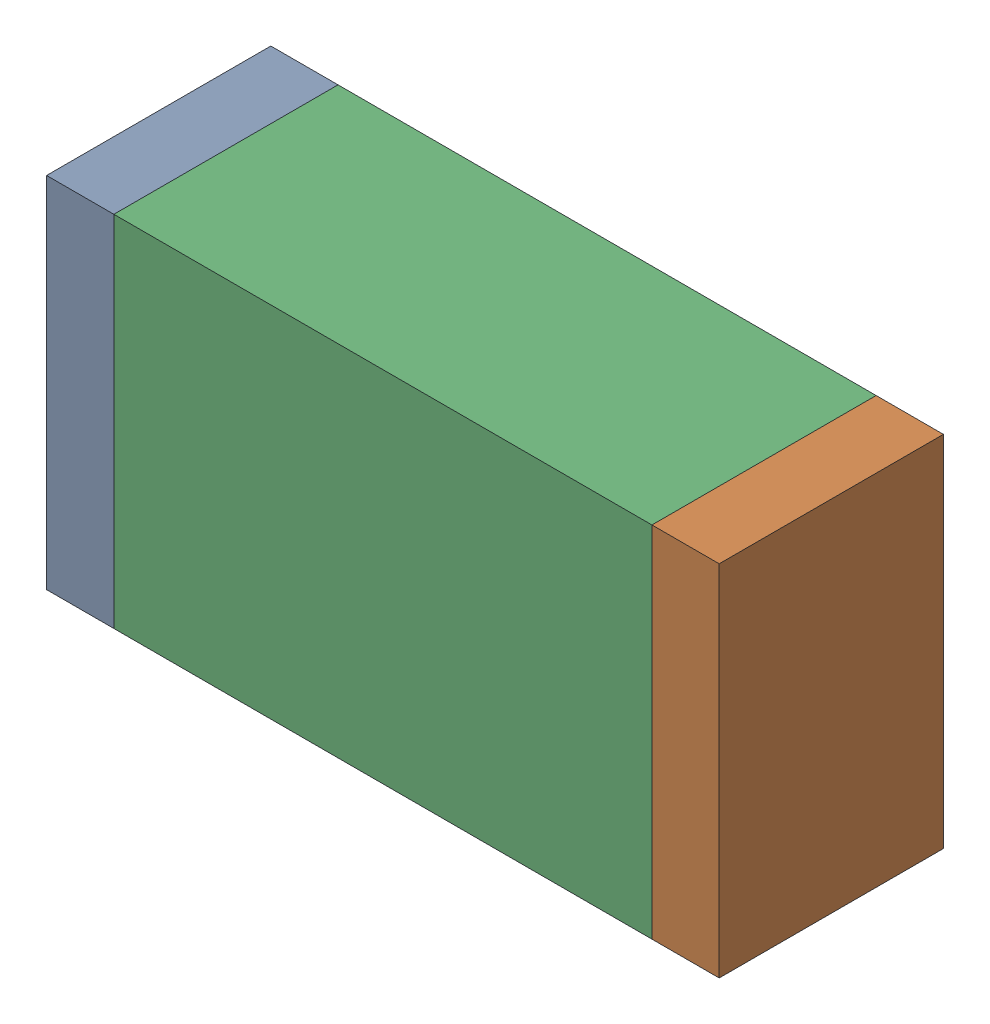
SolidWorks assembly R38, configuration Default. Lengths in mm.
Overall size (1.5 0.8 0.5).
6 component instances, 2 part files, 0 mates.
Components (placement in the parent):
- 836752496-1: 836752496 [Default] at (115.225 51.05 0) size (0.15 0.8 0.5)
  - Extruded_2-1: Extruded_2 [Default] at origin size (0.15 0.8 0.5)
- 836752496-2: 836752496 [Default] at (116.575 51.05 0) size (0.15 0.8 0.5)
  - Extruded_2-1: Extruded_2 [Default] at origin size (0.15 0.8 0.5)
- 836752368-1: 836752368 [Default] at (115.9 51.05 0) size (1.2 0.8 0.5)
  - Extruded-1: Extruded [Default] at origin size (1.2 0.8 0.5)
